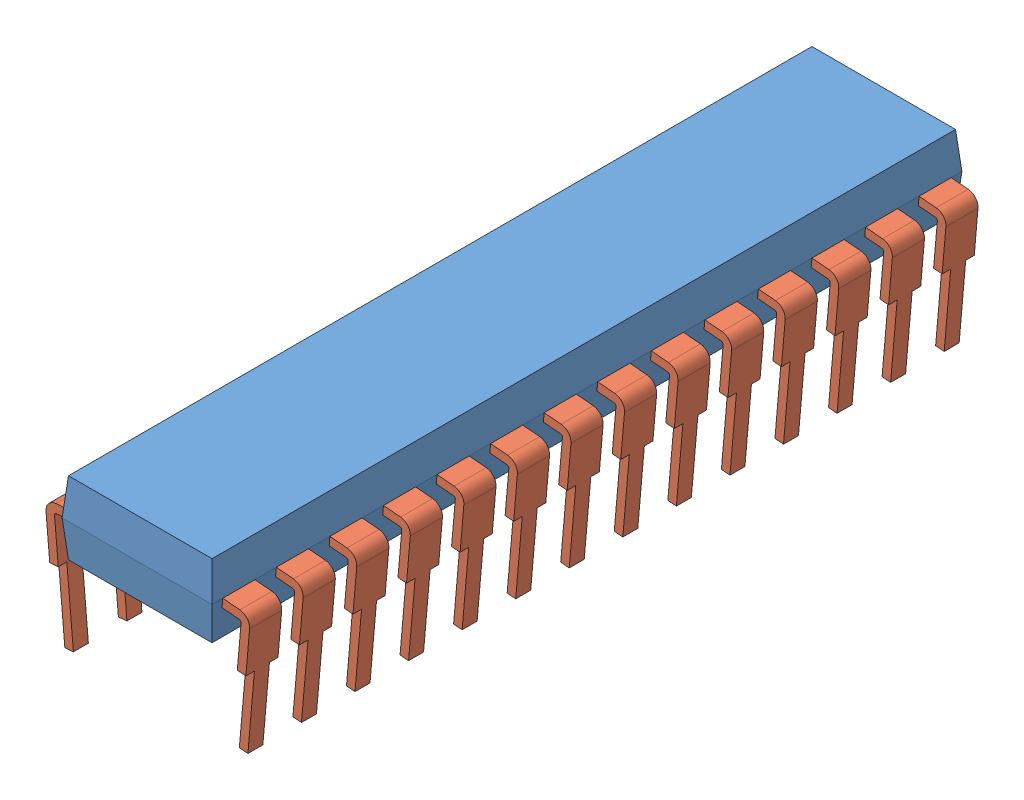
SolidWorks assembly Assem1, configuration Default. Lengths in mm.
Overall size (9.59 7.79 35).
29 component instances, 2 part files, 6 mates.
Components (placement in the parent):
- pin1-1: pin1 [Default] at (7.7092 18.3263 45.3028) size (7 3.4 35)
- pin2-1: pin2 [Default] at (13.0157 18.4744 43.3028) x (0.996195 -0.087156 0) z (0 0 1) size (3 6 1.5)
- pin2-34: pin2 [Default] at (13.0157 18.4744 40.8028) x (0.996195 -0.087156 0) z (0 0 1) size (3 6 1.5)
- pin2-35: pin2 [Default] at (13.0157 18.4744 38.3028) x (0.996195 -0.087156 0) z (0 0 1) size (3 6 1.5)
- pin2-36: pin2 [Default] at (13.0157 18.4744 35.8028) x (0.996195 -0.087156 0) z (0 0 1) size (3 6 1.5)
- pin2-37: pin2 [Default] at (13.0157 18.4744 33.3028) x (0.996195 -0.087156 0) z (0 0 1) size (3 6 1.5)
- pin2-38: pin2 [Default] at (13.0157 18.4744 30.8028) x (0.996195 -0.087156 0) z (0 0 1) size (3 6 1.5)
- pin2-39: pin2 [Default] at (13.0157 18.4744 28.3028) x (0.996195 -0.087156 0) z (0 0 1) size (3 6 1.5)
- pin2-40: pin2 [Default] at (13.0157 18.4744 25.8028) x (0.996195 -0.087156 0) z (0 0 1) size (3 6 1.5)
- pin2-41: pin2 [Default] at (13.0157 18.4744 23.3028) x (0.996195 -0.087156 0) z (0 0 1) size (3 6 1.5)
- pin2-42: pin2 [Default] at (13.0157 18.4744 20.8028) x (0.996195 -0.087156 0) z (0 0 1) size (3 6 1.5)
- pin2-43: pin2 [Default] at (13.0157 18.4744 18.3028) x (0.996195 -0.087156 0) z (0 0 1) size (3 6 1.5)
- pin2-44: pin2 [Default] at (13.0157 18.4744 15.8028) x (0.996195 -0.087156 0) z (0 0 1) size (3 6 1.5)
- pin2-45: pin2 [Default] at (13.0157 18.4744 13.3028) x (0.996195 -0.087156 0) z (0 0 1) size (3 6 1.5)
- pin2-46: pin2 [Default] at (13.0157 18.4744 10.8028) x (0.996195 -0.087156 0) z (0 0 1) size (3 6 1.5)
- pin2-49: pin2 [Default] at (9.4028 18.4744 44.8028) x (-0.996195 -0.087156 0) z (0 0 -1) size (3 6 1.5)
- pin2-50: pin2 [Default] at (9.4028 18.4744 42.3028) x (-0.996195 -0.087156 0) z (0 0 -1) size (3 6 1.5)
- pin2-51: pin2 [Default] at (9.4028 18.4744 39.8028) x (-0.996195 -0.087156 0) z (0 0 -1) size (3 6 1.5)
- pin2-52: pin2 [Default] at (9.4028 18.4744 37.3028) x (-0.996195 -0.087156 0) z (0 0 -1) size (3 6 1.5)
- pin2-53: pin2 [Default] at (9.4028 18.4744 34.8028) x (-0.996195 -0.087156 0) z (0 0 -1) size (3 6 1.5)
- pin2-54: pin2 [Default] at (9.4028 18.4744 32.3028) x (-0.996195 -0.087156 0) z (0 0 -1) size (3 6 1.5)
- pin2-55: pin2 [Default] at (9.4028 18.4744 29.8028) x (-0.996195 -0.087156 0) z (0 0 -1) size (3 6 1.5)
- pin2-56: pin2 [Default] at (9.4028 18.4744 27.3028) x (-0.996195 -0.087156 0) z (0 0 -1) size (3 6 1.5)
- pin2-57: pin2 [Default] at (9.4028 18.4744 24.8028) x (-0.996195 -0.087156 0) z (0 0 -1) size (3 6 1.5)
- pin2-58: pin2 [Default] at (9.4028 18.4744 22.3028) x (-0.996195 -0.087156 0) z (0 0 -1) size (3 6 1.5)
- pin2-59: pin2 [Default] at (9.4028 18.4744 19.8028) x (-0.996195 -0.087156 0) z (0 0 -1) size (3 6 1.5)
- pin2-60: pin2 [Default] at (9.4028 18.4744 17.3028) x (-0.996195 -0.087156 0) z (0 0 -1) size (3 6 1.5)
- pin2-61: pin2 [Default] at (9.4028 18.4744 14.8028) x (-0.996195 -0.087156 0) z (0 0 -1) size (3 6 1.5)
- pin2-62: pin2 [Default] at (9.4028 18.4744 12.3028) x (-0.996195 -0.087156 0) z (0 0 -1) size (3 6 1.5)
Mates (geometry in assembly coordinates):
- Distance3: distance = 0 mm: plane of pin2-1 through (13.0157 18.4744 44.8028) normal (-0.996195 0.087156 0); plane of pin1-1 through (12.9625 17.8667 45.3028) normal (0.996195 -0.087156 0)
- Coincident15: coincident: plane of pin1-1 through (13.0157 18.4744 44.8028) normal (-0.087156 -0.996195 0); plane of pin2-1 through (13.0157 18.4744 44.8028) normal (0.087156 0.996195 0)
- Coincident17: coincident: plane of pin1-1 through (13.0157 18.4744 44.8028) normal (0 0 -1); plane of pin2-1 through (15.4626 17.7585 44.8028) normal (0 0 1)
- Coincident23: coincident: plane of pin1-1 through (9.4559 17.8667 45.3028) normal (-0.996195 -0.087156 0); plane of pin2-49 through (9.4028 18.4744 43.3028) normal (0.996195 0.087156 0)
- Coincident24: coincident: plane of pin1-1 through (9.4028 18.4744 44.8028) normal (0.087156 -0.996195 0); plane of pin2-49 through (9.4028 18.4744 43.3028) normal (-0.087156 0.996195 0)
- Coincident25: coincident: plane of pin1-1 through (9.4028 18.4744 44.8028) normal (0 0 -1); plane of pin2-49 through (6.9559 17.7585 44.8028) normal (0 0 1)
